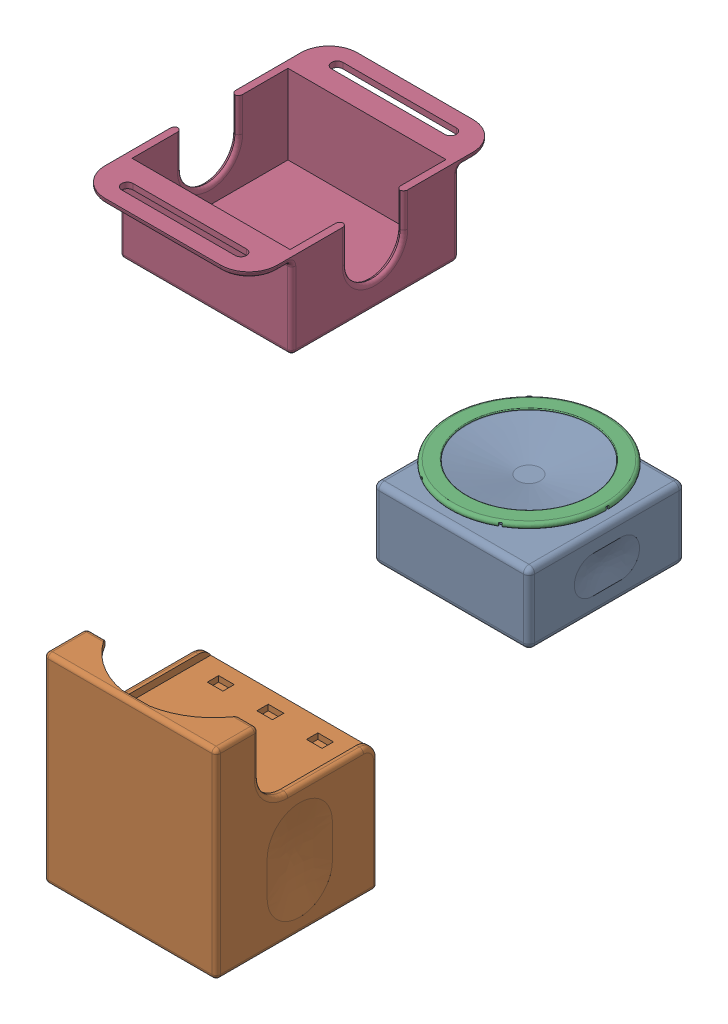
SolidWorks assembly SmartStetho, configuration Default. Lengths in mm.
Overall size (147.35 122.24 186.52).
4 component instances, 4 part files, 3 mates.
Components (placement in the parent):
- module-1: module [Default] at origin size (55.78 31 55)
- holder-1: holder [Default] at (0 0 111.2378) x (-1 0 0) z (0 0 -1) size (62.1 70.5 57.2)
- Part1-1: Part1 [Default] at origin size (55.64 1.79 55.53) (hidden)
- wearable-1: wearable [Default] at (-85.9278 51.7444 -1.2794) size (60.75 30.5 89)
Mates (geometry in assembly coordinates):
- Coincident1: coincident anti-aligned: plane of module-1 through (-27.5 -27 27.5) normal (0 0 1); plane of holder-1 through (0 0 27.5) normal (0 0 -1)
- Width1: width anti-aligned: plane of holder-1 through (27.875 -1.5 138.7378) normal (-1 0 0); plane of module-1 through (-27.875 -1.5 138.7378) normal (1 0 0); plane of holder-1 through (27.5 -27 -27.5) normal (1 0 0); plane of module-1 through (-27.5 -27 -27.5) normal (-1 0 0)
- Coincident2: coincident anti-aligned: plane of module-1 through (0 -27 0) normal (0 -1 0); plane of holder-1 through (27.875 -27 138.7378) normal (0 1 0)
